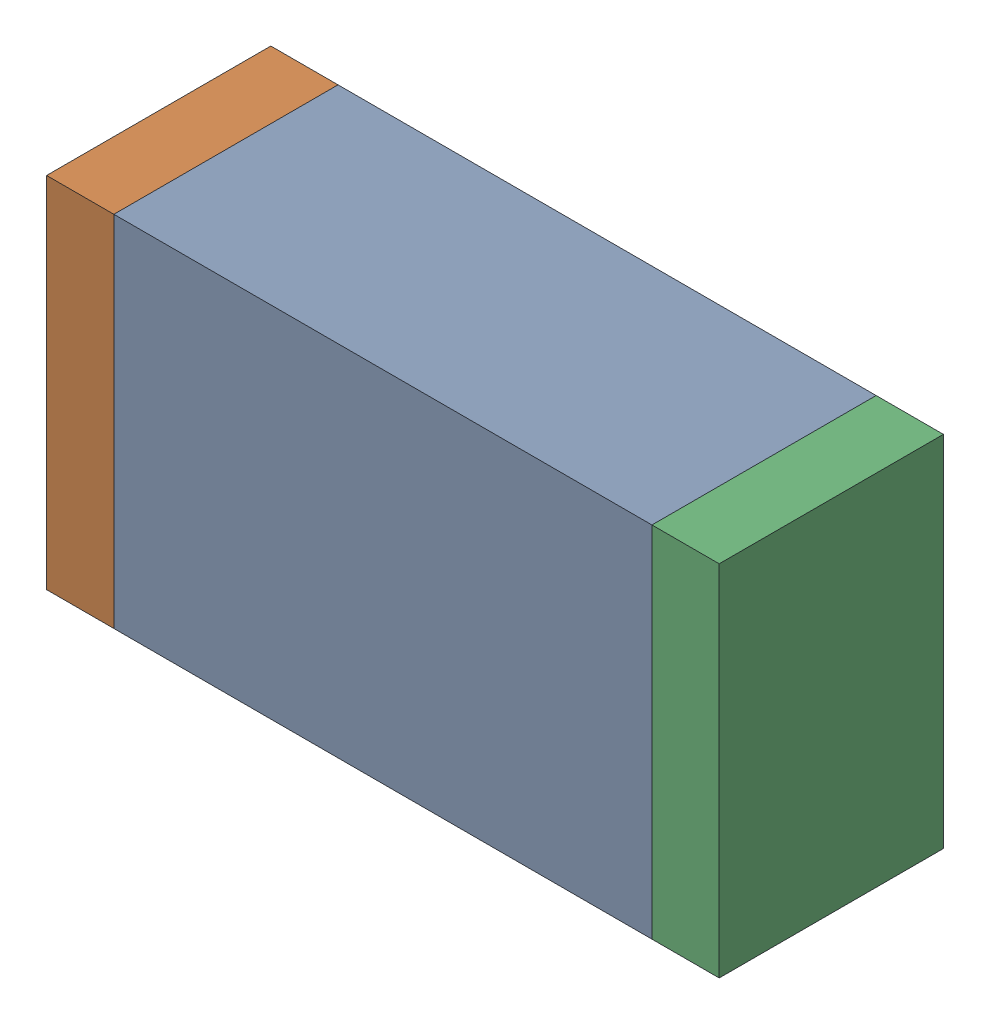
SolidWorks assembly R14, configuration Default. Lengths in mm.
Overall size (1.5 0.8 0.5).
6 component instances, 2 part files, 0 mates.
Components (placement in the parent):
- 836752368-1: 836752368 [Default] at (118.55 39.35 0) size (1.2 0.8 0.5)
  - Extruded-1: Extruded [Default] at origin size (1.2 0.8 0.5)
- 836752496-1: 836752496 [Default] at (117.875 39.35 0) size (0.15 0.8 0.5)
  - Extruded_2-1: Extruded_2 [Default] at origin size (0.15 0.8 0.5)
- 836752496-2: 836752496 [Default] at (119.225 39.35 0) size (0.15 0.8 0.5)
  - Extruded_2-1: Extruded_2 [Default] at origin size (0.15 0.8 0.5)
